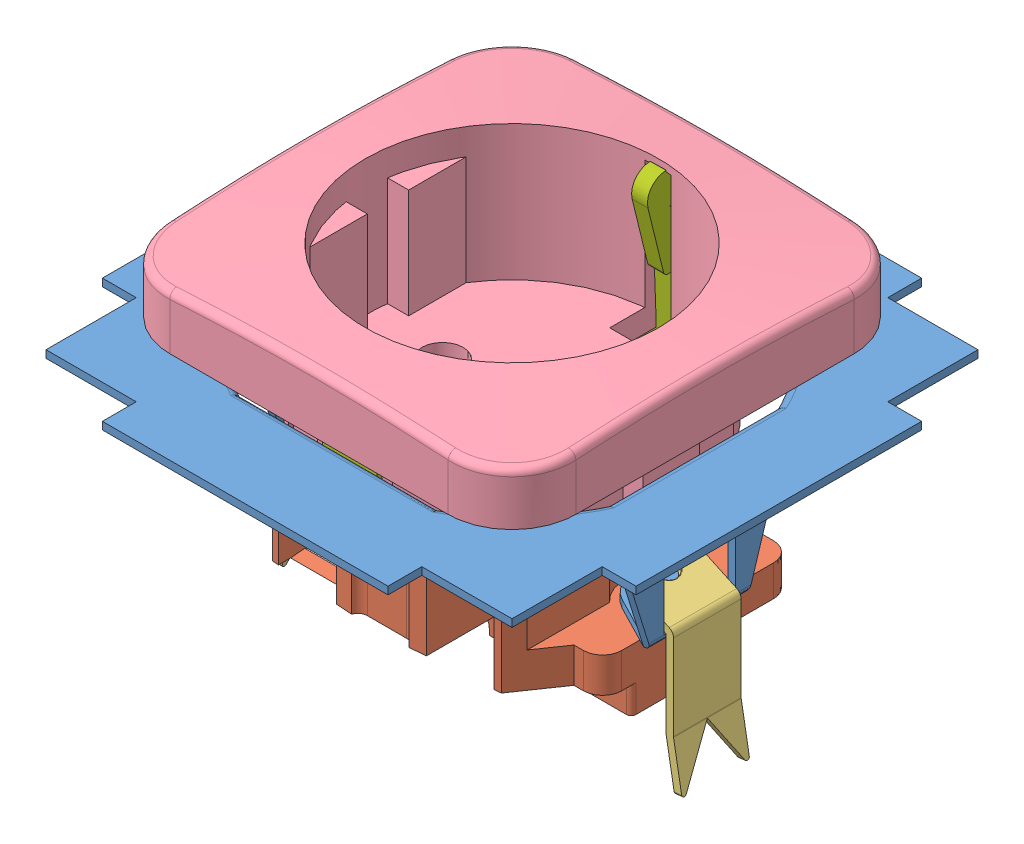
SolidWorks assembly Steckdose, configuration Standard. Lengths in mm.
Overall size (71 48.85 71).
8 component instances, 7 part files, 22 mates.
Components (placement in the parent):
- Montageplatte.02-1: Montageplatte.02 [Standard] at (-129.6803 11 128.1202) x (1 0 0) z (0 1 0) size (71 71 18.97)
- Halter-1: Halter [Standard] at (-129.6803 11 128.1202) x (1 0 0) z (0 1 0) size (45.97 31.9 15.37)
- Kralle.04-1: Kralle.04 [Standard] at (-126.9942 12.4168 128.1202) x (0.996195 -0.087156 0) z (0.087156 0.996195 0) size (8.78 9 23.36)
- Kralle.04-2: Kralle.04 [Standard] at (21.6299 12.4168 26.282) x (-0.996195 -0.087156 0) z (-0.087156 0.996195 0) size (8.78 9 23.36)
- Buchse-1: Buchse [Standard] at (-129.6803 10.7714 128.1202) x (1 0 0) z (0 1 0) size (64.03 64.03 27)
- Stromklemme_1.02-1: Stromklemme_1.02 [Standard] at (-129.6803 11 127.9932) x (1 0 0) z (0 1 0) size (8.38 19.82 12.51)
- Stromklemme_2.02-1: Stromklemme_2.02 [Standard] at (-129.6803 11 127.9932) x (1 0 0) z (0 1 0) size (8.38 19.82 12.51)
- Erdleiter-1: Erdleiter [Standard] at (-129.6803 11 128.1202) x (1 0 0) z (0 1 0) size (7.24 44.01 27.12)
Mates (geometry in assembly coordinates):
- Abstand1: distance = 0.25 mm anti-aligned: plane of Kralle.04-1 through (-76.9514 -8.7605 72.7011) normal (0 0 -1); plane of Montageplatte.02-1 through (-95.2822 -9.4704 72.4511) normal (0 0 1)
- Abstand2: distance = 0.25 mm anti-aligned: plane of Kralle.04-2 through (-28.4129 -8.7605 81.7011) normal (0 0 1); plane of Montageplatte.02-1 through (-95.2822 -16.9704 81.9511) normal (0 0 -1)
- Konzentrisch1: concentric aligned: cylinder of Montageplatte.02-1 through (-32.7759 -17.9704 77.2011) axis (0 1 0) radius 2; cylinder of Halter-1 through (-32.7759 -27.8383 77.2011) axis (0 1 0) radius 1.5
- Konzentrisch2: concentric aligned: cylinder of Montageplatte.02-1 through (-72.5884 -17.9704 77.2011) axis (0 1 0) radius 2; cylinder of Halter-1 through (-72.5884 -27.8383 77.2011) axis (0 1 0) radius 1.5
- Deckungsgleich9: coincident anti-aligned: plane of Montageplatte.02-1 through (-33.534 -17.9704 75.4866) normal (0 -1 0); plane of Halter-1 through (-72.4941 -17.9704 77.3302) normal (0 1 0)
- Abstand3: distance = 2 mm anti-aligned: plane of Halter-1 through (-75.6691 -26.3016 78.7886) normal (-1 0 0); plane of Kralle.04-1 through (-77.6691 -28.4819 77.2011) normal (1 0 0)
- Deckungsgleich13: coincident: line of Montageplatte.02-1 through (-77.6821 -16.9704 81.9511) axis (0 0 -1); plane of Kralle.04-1 through (-69.5303 -13.1691 77.2011) normal (0.422618 -0.906308 0)
- Abstand4: distance = 2 mm anti-aligned: plane of Kralle.04-2 through (-27.6951 -28.4819 77.2011) normal (-1 0 0); plane of Halter-1 through (-29.6951 -26.3016 78.7886) normal (1 0 0)
- Deckungsgleich15: coincident: line of Montageplatte.02-1 through (-27.6821 -16.9704 72.4511) axis (0 0 1); plane of Kralle.04-2 through (-35.834 -13.1691 77.2011) normal (-0.422618 -0.906308 0)
- Deckungsgleich16: coincident anti-aligned: plane of Halter-1 through (-58.7781 -19.3928 59.6472) normal (0 1 0); plane of Stromklemme_2.02-1 through (-58.7781 -19.3928 59.5202) normal (0 -1 0)
- Deckungsgleich17: coincident anti-aligned: plane of Halter-1 through (-38.4581 -19.3928 59.6472) normal (0 1 0); plane of Stromklemme_1.02-1 through (-38.4581 -19.3928 59.5202) normal (0 -1 0)
- Deckungsgleich18: coincident anti-aligned: plane of Halter-1 through (-16.8044 -19.3928 65.8854) normal (0 0 1); plane of Stromklemme_2.02-1 through (-20.8907 -10.9346 65.8854) normal (0 0 -1)
- Deckungsgleich19: coincident anti-aligned: plane of Halter-1 through (-16.8044 -19.3928 65.8854) normal (0 0 1); plane of Stromklemme_1.02-1 through (-0.5707 -10.9346 65.8854) normal (0 0 -1)
- Deckungsgleich20: coincident anti-aligned: plane of Halter-1 through (-58.6511 -29.7817 90.4218) normal (-1 0 0); plane of Stromklemme_2.02-1 through (-58.6511 -29.7817 90.2948) normal (1 0 0)
- Deckungsgleich21: coincident anti-aligned: plane of Halter-1 through (-46.7131 -19.3928 78.7886) normal (1 0 0); plane of Stromklemme_1.02-1 through (-46.7131 -20.6234 90.2948) normal (-1 0 0)
- Deckungsgleich22: coincident anti-aligned: plane of Halter-1 through (-48.8721 -14.6176 62.8374) normal (0 1 0); plane of Erdleiter-1 through (-56.3016 -14.6176 77.2011) normal (0 -1 0)
- Konzentrisch5: concentric anti-aligned: cylinder of Halter-1 through (-52.6821 -10.9346 77.2011) axis (0 -1 0) radius 1.5875; cylinder of Erdleiter-1 through (-52.6821 -14.6176 77.2011) axis (0 1 0) radius 1.5875
- Parallel5: parallel anti-aligned: plane of Erdleiter-1 through (-49.0626 -12.0776 94.5376) normal (1 0 0); plane of Halter-1 through (-48.8721 -14.6176 62.8374) normal (-1 0 0)
- Konzentrisch6: concentric aligned: cylinder of Halter-1 through (-52.6821 -10.9346 77.2011) axis (0 -1 0) radius 1.5875; cylinder of Buchse-1 through (-52.6821 15.9714 77.2011) axis (0 -1 0) radius 1.5
- Deckungsgleich24: coincident anti-aligned: plane of Buchse-1 through (-35.9321 -13.7286 77.2011) normal (0 -1 0); plane of Erdleiter-1 through (-56.3016 -13.7286 77.2011) normal (0 1 0)
- Parallel6: parallel anti-aligned: plane of Halter-1 through (-48.8721 -14.6176 62.8374) normal (-1 0 0); plane of Buchse-1 through (-49.1821 -6.7286 81.7011) normal (1 0 0)
- Deckungsgleich26: coincident anti-aligned: plane of Montageplatte.02-1 through (-88.1821 0 111.2011) normal (0 -1 0); plane of assembly through (0 0 0) normal (0 1 0)
